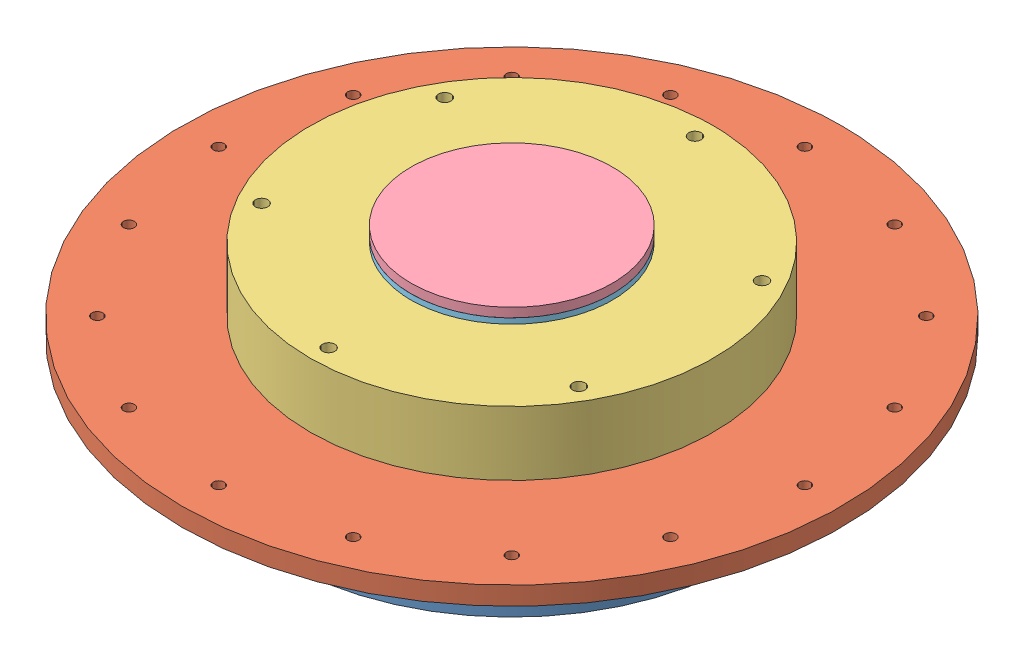
SolidWorks assembly assem center hub, configuration Default. Lengths in mm.
Overall size (360 97 360).
10 component instances, 9 part files, 17 mates.
Components (placement in the parent):
- base support-1: base support [Default] at origin size (250 35 250)
- upper bearing retainer ring-1: upper bearing retainer ring [Default] at (0 44.005 0) x (-1 0 0) z (0 0 -1) size (360 10 360)
- rotary hub cover-2: rotary hub cover [Default] at (0 54.005 0) x (-1 0 0) z (0 0 -1) size (220 35 220)
- shaft of center hub-1: shaft of center hub [Default] at (0 22 0) size (110 75 110)
- brass bushing 110-2: brass bushing 110 [Default] at (0 25 0) x (0.999788 0 0.020577) z (-0.020577 0 0.999788) size (110 67 110)
- SKF 51224-1: SKF 51224 [Default] at (-55.2182 -49.5365 -118.9218) x (1 0 -0.000871) z (0.000871 0 1) size (190.86 39 190.86)
  - 51224_bottom-1: 51224_bottom [Default] at (55.1145 86.7365 118.9699) x (1 0 0) z (0 0 -1) size (170 12.2 170)
  - 51224_middle-1: 51224_middle [Default] at (55.1145 89.474 118.9699) x (0.991331 0 0.131388) z (-0.131388 0 0.991331) size (170 18.26 170)
  - 51224_top-1: 51224_top [Default] at (55.1145 101.3415 118.9699) x (0.999827 0 -0.018578) z (0.018578 0 0.999827) size (170 12.2 170)
- turntable flange plate-1: turntable flange plate [Default] at (0 89.005 0) x (0.866025 0 0.5) z (-0.5 0 0.866025) size (230 15 230) (hidden)
Mates (geometry in assembly coordinates):
- Coincident24: coincident: plane of base support-1 through (0 25 0) normal (0 1 0); plane of SKF 51224-1/51224_bottom-1 through (0 25 0) normal (0 -1 0)
- Concentric32: concentric: cylinder of shaft of center hub-1 through (0 97 0) axis (0 1 0) radius 50; cylinder of brass bushing 110-2 through (0 92 0) axis (0 -1 0) radius 50
- Coincident25: coincident: plane of shaft of center hub-1 through (0 92 -50) normal (0 -1 0); plane of brass bushing 110-2 through (0 92 0) normal (0 1 0)
- Concentric33: concentric: cylinder of base support-1 through (0 25 0) axis (0 -1 0) radius 125; cylinder of shaft of center hub-1 through (0 97 0) axis (0 1 0) radius 55
- Coincident26: coincident: plane of base support-1 through (0 22 0) normal (0 1 0); plane of shaft of center hub-1 through (0 22 0) normal (0 -1 0)
- Concentric34: concentric: cylinder of base support-1 through (24.7487 39.1421 24.7487) axis (0 -1 0) radius 5; cylinder of shaft of center hub-1 through (24.7487 52 24.7487) axis (0 -1 0) radius 4
- Coincident27: coincident: plane of upper bearing retainer ring-1 through (0 54.005 0) normal (0 1 0); plane of rotary hub cover-2 through (0 54.005 0) normal (0 -1 0)
- Concentric35: concentric: cylinder of upper bearing retainer ring-1 through (0 54.005 0) axis (0 -1 0) radius 180; cylinder of rotary hub cover-2 through (0 89.005 0) axis (0 -1 0) radius 110
- Concentric36: concentric: cylinder of upper bearing retainer ring-1 through (0 54.005 -100) axis (0 -1 0) radius 4; cylinder of rotary hub cover-2 through (0 89.005 -100) axis (0 -1 0) radius 3.4
- Concentric37: concentric: cylinder of rotary hub cover-2 through (0 89.005 0) axis (0 -1 0) radius 55; cylinder of brass bushing 110-2 through (0 92 0) axis (0 -1 0) radius 55
- Coincident28: coincident: plane of rotary hub cover-2 through (0 64.005 0) normal (0 -1 0); plane of SKF 51224-1/51224_top-1 through (0 64.005 0) normal (0 1 0)
- Parallel4: parallel: plane of upper bearing retainer ring-1 through (0 44.005 0) normal (0 0 -1); plane of assembly through (0 0 0) normal (0 0 1)
- Coincident29: coordinate: point of base support-1; point of assembly
- Parallel5: parallel: plane of base support-1 through (0 0 0) normal (0 0 1); plane of assembly through (0 0 0) normal (0 0 1)
- Coincident30: coincident: plane of rotary hub cover-2 through (0 89.005 0) normal (0 1 0); plane of turntable flange plate-1 through (0 89.005 0) normal (0 -1 0)
- Concentric38: concentric: cylinder of rotary hub cover-2 through (0 89.005 0) axis (0 -1 0) radius 110; cylinder of turntable flange plate-1 through (0 104.005 0) axis (0 -1 0) radius 115
- Concentric39: concentric: cylinder of rotary hub cover-2 through (-86.6025 89.005 -50) axis (0 -1 0) radius 3.4; cylinder of turntable flange plate-1 through (-86.6025 104.005 -50) axis (0 -1 0) radius 6.5
